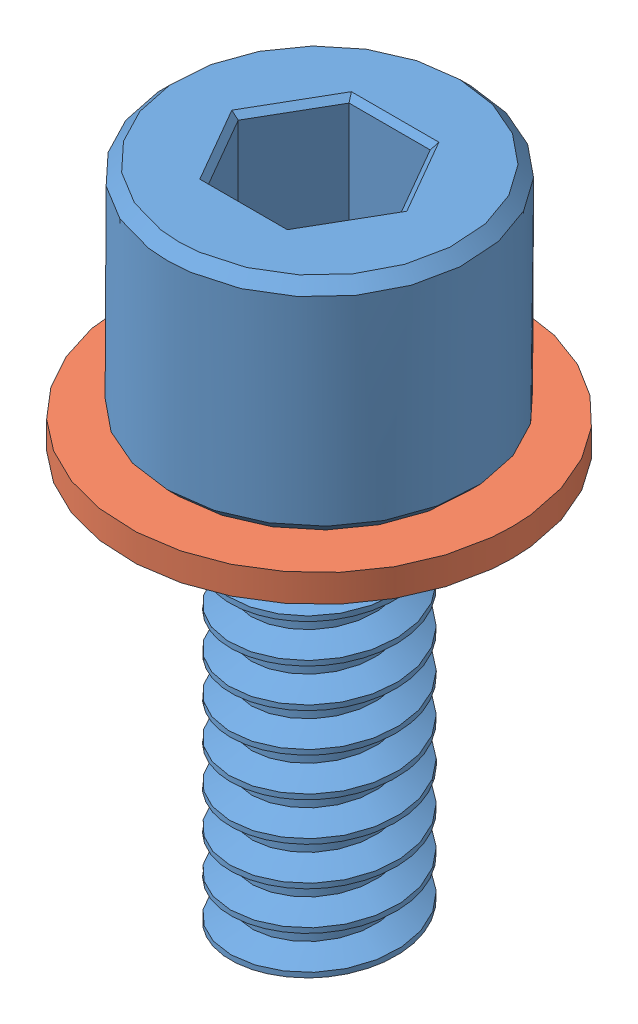
SolidWorks assembly Fixing_M3, configuration По умолчанию. Lengths in mm.
Overall size (7 12.27 7).
2 component instances, 2 part files, 2 mates.
Components (placement in the parent):
- M3_6mm SS Bolt-1: M3_6mm SS Bolt [Default] at origin size (5.5 12.27 5.5)
- Spacer_M3-1: Spacer_M3 [По умолчанию] x (1 0 0) z (0 -1 0) size (7 7 0.5)
Mates (geometry in assembly coordinates):
- Концентричный1: concentric anti-aligned: cylinder of M3_6mm SS Bolt-1 through (0 4 0) axis (0 -1 0) radius 2.75; cylinder of Spacer_M3-1 through (0 -0.5 0) axis (0 1 0) radius 1.6
- Совпадение1: coincident anti-aligned: plane of M3_6mm SS Bolt-1 through (0 0 0) normal (0 -1 0); plane of Spacer_M3-1 through (0 0 0) normal (0 1 0)
